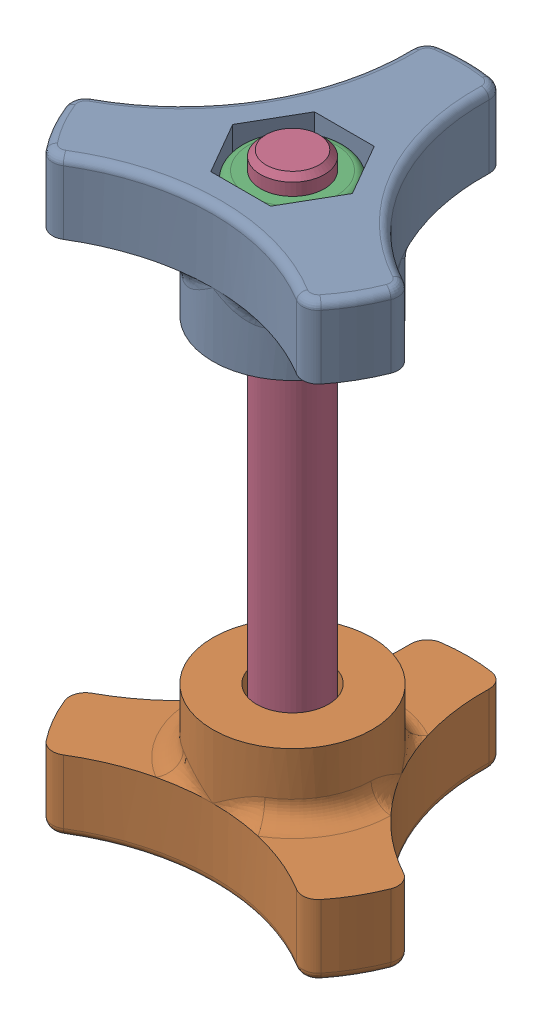
SolidWorks assembly TR23-RC-0700_40mm, configuration Default. Lengths in mm.
Overall size (41.18 75.3 36.41).
4 component instances, 4 part files, 0 mates.
Components (placement in the parent):
- TR23-RC-0050-1: TR23-RC-0050 [Default] at origin size (41.18 17 36.41)
- TR23-RC-0051-1: TR23-RC-0051 [Default] at (0 -40 0) x (-1 0 0) z (0 0 1) size (41.18 17 36.41)
- ISO 10511 M8 Locking Nut-1: ISO 10511 M8 Locking Nut [Default] at (0 9 0) x (0 0 -1) z (1 0 0) size (13 6.76 15.01)
- ISO 4017 - M8 x 70-N_ISO 4017 - M8 x 70-N-1: ISO 4017 - M8 x 70-N_ISO 4017 - M8 x 70-N [Default] at (0 -57.3 0) x (0 1 0) z (0 0 1) size (75.3 15.01 13)
